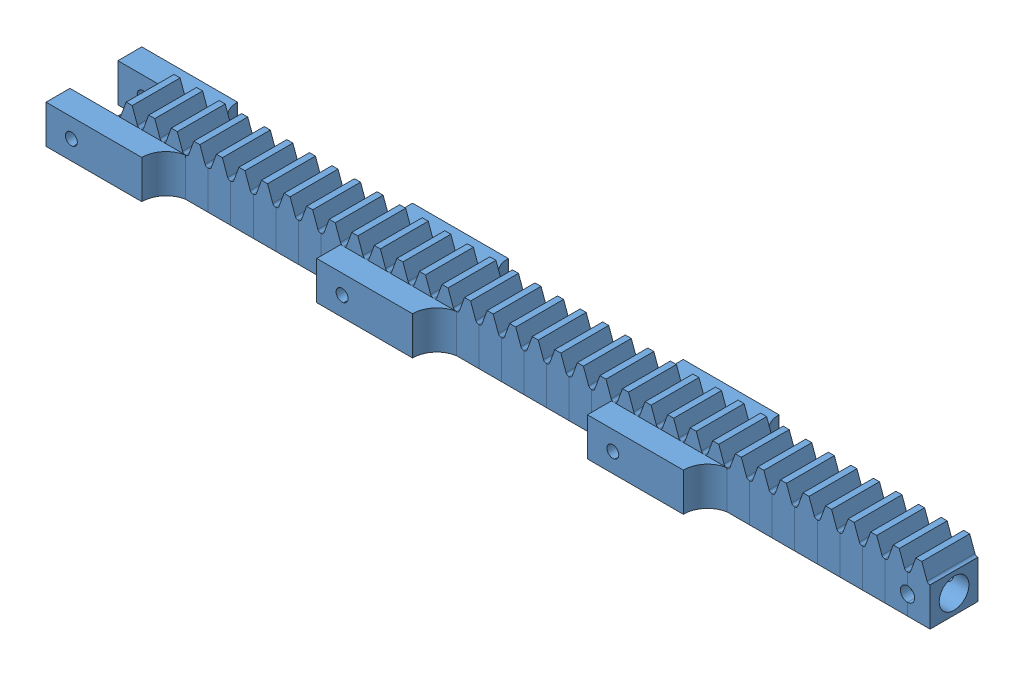
SolidWorks assembly ForkRackPinionPieceAssembly, configuration Default. Lengths in mm.
Overall size (179.57 11.38 20).
3 component instances, 1 part files, 0 mates.
Components (placement in the parent):
- ForkRackPinionPiece-1: ForkRackPinionPiece [Default] at (56.2955 35.7755 37.5358) size (66.53 11.38 20)
- ForkRackPinionPiece-2: ForkRackPinionPiece [Default] at (112.8155 35.7755 37.5358) size (66.53 11.38 20)
- ForkRackPinionPiece-3: ForkRackPinionPiece [Default] at (169.3355 35.7755 37.5358) size (66.53 11.38 20)
